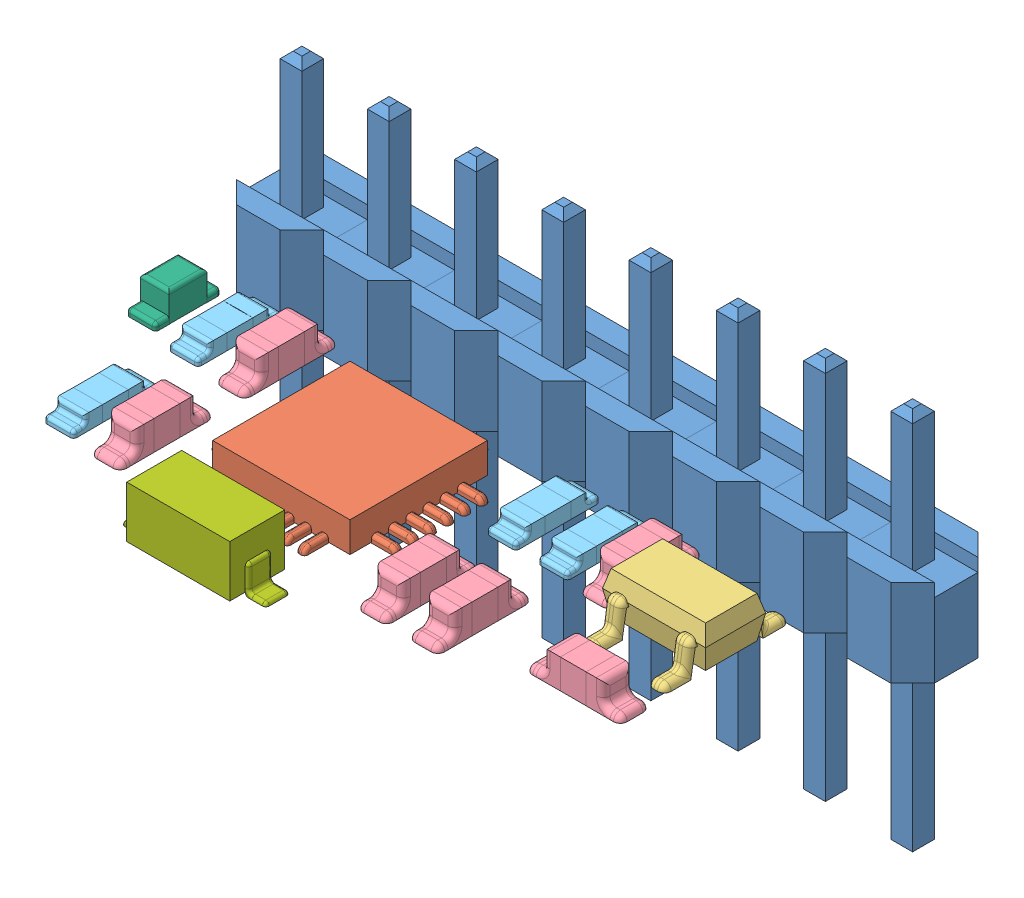
SolidWorks assembly MPU 6050 IMU, configuration Default. Lengths in mm.
Overall size (20.63 11.18 13.88).
23 component instances, 8 part files, 33 mates.
Components (placement in the parent):
- base-1: base [Default] at (7.2489 10.9584 16.5726) (suppressed, hidden)
- pin header-1: pin header [Default] at (16.0246 10.3869 9.8416) x (-1 0 0) z (0 0 1) size (2.54 11.18 2.54)
- sensor chip-1: sensor chip [Default] at (7.2489 11.5499 17.4466) size (5.4 0.9 5.4)
- S2NH chip-1: S2NH chip [Default] at (16.1026 12.3799 16.5726) size (3 1.35 3.65)
- Resistor small-3: Resistor small [Default] at (16.1026 11.5314 19.3726) size (2.75 0.99 1)
- Resistor small-4: Resistor small [Default] at (13.9776 11.5314 15.6976) x (0 0 -1) z (1 0 0) size (2.75 0.99 1)
- Resistor small black-3: Resistor small black [Default] at (12.6276 11.5299 15.6976) x (0 0 1) z (-1 0 0) size (2.45 0.6 1.02)
- Resistor small-5: Resistor small [Default] at (12.6276 11.5314 19.3216) x (0 0 -1) z (1 0 0) size (2.75 0.99 1)
- Resistor small-8: Resistor small [Default] at (3.3702 11.5314 15.6976) x (0 0 1) z (-1 0 0) size (2.75 0.99 1)
- Small LED-1: Small LED [Default] at (0.3652 11.5299 15.6976) size (0.85 0.84 1.9)
- Resistor small black-6: Resistor small black [Default] at (1.8702 11.5299 19.3216) x (0 0 1) z (-1 0 0) size (2.45 0.6 1.02)
- Resistor black-1: Resistor black [Default] at (7.2489 12.3799 21.6466) size (4.2 1.6 1.6)
- pin header-2: pin header [Default] at (13.4846 10.3869 9.8416) x (-1 0 0) z (0 0 1) size (2.54 11.18 2.54)
- pin header-3: pin header [Default] at (10.9446 10.3869 9.8416) x (-1 0 0) z (0 0 1) size (2.54 11.18 2.54)
- pin header-4: pin header [Default] at (8.4046 10.3869 9.8416) x (-1 0 0) z (0 0 1) size (2.54 11.18 2.54)
- pin header-5: pin header [Default] at (5.8646 10.3869 9.8416) x (-1 0 0) z (0 0 1) size (2.54 11.18 2.54)
- pin header-6: pin header [Default] at (3.3246 10.3869 9.8416) x (-1 0 0) z (0 0 1) size (2.54 11.18 2.54)
- pin header-7: pin header [Default] at (0.7846 10.3869 9.8416) x (-1 0 0) z (0 0 1) size (2.54 11.18 2.54)
- pin header-8: pin header [Default] at (-1.7554 10.3869 9.8416) x (-1 0 0) z (0 0 1) size (2.54 11.18 2.54)
- Resistor small black-4: Resistor small black [Default] at (11.1276 11.5299 15.6976) x (0 0 1) z (-1 0 0) size (2.45 0.6 1.02)
- Resistor small-6: Resistor small [Default] at (11.1276 11.5314 19.3216) x (0 0 -1) z (1 0 0) size (2.75 0.99 1)
- Resistor small-7: Resistor small [Default] at (3.3702 11.5314 19.3216) x (0 0 -1) z (1 0 0) size (2.75 0.99 1)
- Resistor small black-5: Resistor small black [Default] at (1.8702 11.5299 15.6968) x (0 0 -1) z (1 0 0) size (2.45 0.6 1.02)
Mates (geometry in assembly coordinates):
- Concentric1: concentric: point of base-1; unknown of pin header-1
- Coincident4: coincident: plane of base-1 through (7.2489 10.3869 16.5726) normal (0 -1 0); plane of pin header-1 through (16.0246 10.3869 9.8416) normal (0 1 0)
- Parallel1: parallel: plane of base-1 through (17.8026 11.5299 24.4466) normal (1 0 0); plane of pin header-1 through (17.2946 7.8469 10.4766) normal (1 0 0)
- Coincident6: coincident: plane of base-1 through (7.2489 11.5299 16.5726) normal (0 1 0); plane of sensor chip-1 through (7.2489 11.5299 17.4466) normal (0 -1 0)
- Coincident7: coincident: plane of base-1 through (7.2489 10.9584 16.5726) normal (1 0 0); plane of sensor chip-1 through (7.2489 11.5499 17.4466) normal (1 0 0)
- Distance1: distance = 5 mm aligned: plane of sensor chip-1 through (5.2489 12.4299 19.4466) normal (0 0 1); plane of base-1 through (-3.3048 11.5299 24.4466) normal (0 0 1)
- Coincident8: coincident: plane of base-1 through (7.2489 11.5299 16.5726) normal (0 1 0); plane of S2NH chip-1 through (16.1026 11.5299 16.5726) normal (0 -1 0)
- Coincident9: coincident: plane of base-1 through (7.2489 10.9584 16.5726) normal (0 0 1); plane of S2NH chip-1 through (16.1026 12.3799 16.5726) normal (0 0 1)
- Distance2: distance = 0.2 mm: line of S2NH chip-1 through (17.6026 12.3799 17.4476) axis (0 0 -1); plane of base-1 through (17.8026 11.5299 24.4466) normal (1 0 0)
- Coincident19: coincident: plane of base-1 through (7.2489 11.5299 16.5726) normal (0 1 0); plane of Resistor small-3 through (16.9776 11.5299 19.8026) normal (0 -1 0)
- Coincident20: coincident aligned: plane of S2NH chip-1 through (16.1026 12.3799 16.5726) normal (1 0 0); plane of Resistor small-3 through (16.1026 11.5314 19.3726) normal (1 0 0)
- Distance5: distance = 1.5 mm: line of S2NH chip-1 through (15.3258 12.3799 17.4476) axis (1 0 0); plane of Resistor small-3 through (16.4776 11.5314 18.9476) normal (0 0 -1)
- Coincident22: coincident: plane of base-1 through (7.2489 11.5299 16.5726) normal (0 1 0); plane of Resistor small-4 through (14.4076 11.5299 14.8226) normal (0 -1 0)
- Coincident24: coincident: line of S2NH chip-1 through (16.8794 12.3799 15.6976) axis (-1 0 0); plane of Resistor small-4 through (13.9776 11.5314 15.6976) normal (0 0 -1)
- Distance6: distance = 0.2 mm: plane of Resistor small-4 through (14.4026 11.5314 15.3226) normal (1 0 0); line of S2NH chip-1 through (14.6026 12.3799 15.6976) axis (0 0 1)
- Coincident26: coincident: plane of base-1 through (7.2489 11.5299 16.5726) normal (0 1 0); plane of Resistor small black-3 through (12.2026 11.5299 16.0726) normal (0 -1 0)
- Coincident28: coincident anti-aligned: plane of Resistor small-4 through (13.9776 11.5314 15.6976) normal (0 0 -1); plane of Resistor small black-3 through (12.6276 11.5299 15.6976) normal (0 0 1)
- Distance7: distance = 0.5 mm anti-aligned: plane of Resistor small-4 through (13.5526 11.5314 15.3226) normal (-1 0 0); plane of Resistor small black-3 through (13.0526 11.5299 16.0726) normal (1 0 0)
- Coincident30: coincident: plane of base-1 through (7.2489 11.5299 16.5726) normal (0 1 0); plane of Resistor small-5 through (13.0576 11.5299 18.4466) normal (0 -1 0)
- Coincident31: coincident anti-aligned: plane of Resistor small black-3 through (12.6276 11.5299 15.6976) normal (-1 0 0); plane of Resistor small-5 through (12.6276 11.5314 19.3216) normal (1 0 0)
- Distance8: distance = 4.25 mm aligned: plane of Resistor small-5 through (12.6276 11.5314 20.1966) normal (0 0 1); plane of base-1 through (-3.3048 11.5299 24.4466) normal (0 0 1)
- Coincident33: coincident: plane of base-1 through (7.2489 11.5299 16.5726) normal (0 1 0); plane of Resistor small-8 through (2.9402 11.5299 14.8226) normal (0 -1 0)
- Coincident34: coincident anti-aligned: plane of Resistor small-7 through (3.3702 11.5314 19.3216) normal (1 0 0); plane of Resistor small-8 through (3.3702 11.5314 15.6976) normal (-1 0 0)
- Coincident36: coincident: line of S2NH chip-1 through (15.8794 12.3799 15.6976) axis (-1 0 0); plane of Resistor small-8 through (3.3702 11.5314 15.6976) normal (0 0 1)
- Coincident37: coincident: plane of base-1 through (7.2489 11.5299 16.5726) normal (0 1 0); plane of Small LED-1 through (0.3652 11.5299 15.6976) normal (0 -1 0)
- Coincident38: coincident: line of S2NH chip-1 through (15.8794 12.3799 15.6976) axis (-1 0 0); plane of Small LED-1 through (0.3652 11.5299 15.6976) normal (0 0 1)
- Distance9: distance = 1.5 mm aligned: plane of Small LED-1 through (-0.0548 12.3699 16.2476) normal (-1 0 0); plane of Resistor small black-5 through (1.4452 11.5299 15.3218) normal (-1 0 0)
- Coincident40: coincident: plane of base-1 through (7.2489 11.5299 16.5726) normal (0 1 0); plane of Resistor small black-6 through (1.4452 11.5299 19.6966) normal (0 -1 0)
- Coincident41: coincident anti-aligned: plane of Resistor small black-5 through (1.8702 11.5299 15.6968) normal (1 0 0); plane of Resistor small black-6 through (1.8702 11.5299 19.3216) normal (-1 0 0)
- Coincident42: coincident anti-aligned: plane of Resistor small-7 through (3.3702 11.5314 19.3216) normal (0 0 -1); plane of Resistor small black-6 through (1.8702 11.5299 19.3216) normal (0 0 1)
- Coincident43: coincident: plane of base-1 through (7.2489 11.5299 16.5726) normal (0 1 0); plane of Resistor black-1 through (5.6489 11.5299 21.9966) normal (0 -1 0)
- Coincident44: coincident: plane of base-1 through (7.2489 10.9584 16.5726) normal (1 0 0); plane of Resistor black-1 through (7.2489 12.3799 21.6466) normal (1 0 0)
- Distance10: distance = 2 mm aligned: plane of Resistor black-1 through (5.7489 13.1299 22.4466) normal (0 0 1); plane of base-1 through (-3.3048 11.5299 24.4466) normal (0 0 1)
